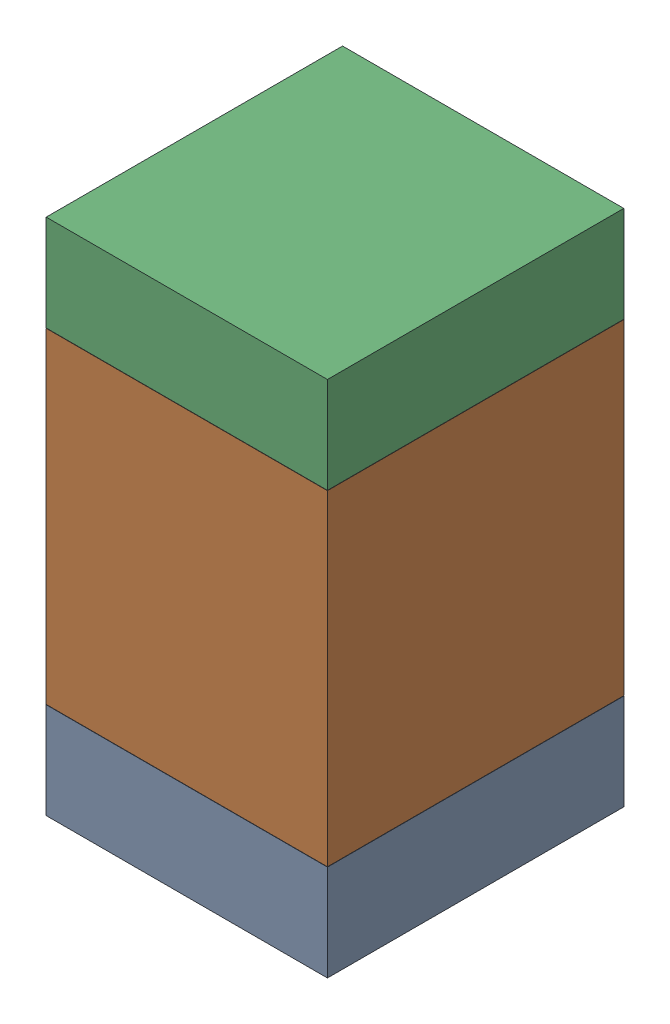
SolidWorks assembly R3, configuration Default. Lengths in mm.
Overall size (0.95 1.75 1).
6 component instances, 2 part files, 0 mates.
Components (placement in the parent):
- 6575495072-1: 6575495072 [Default] at (3.683 42.5945 0) size (0.95 0.32 1)
  - Extruded_6-1: Extruded_6 [Default] at origin size (0.95 0.32 1)
- 6575494912-1: 6575494912 [Default] at (3.683 43.307 0) size (0.95 1.1 1)
  - Extruded_7-1: Extruded_7 [Default] at origin size (0.95 1.1 1)
- 6575495072-2: 6575495072 [Default] at (3.683 44.0195 0) size (0.95 0.32 1)
  - Extruded_6-1: Extruded_6 [Default] at origin size (0.95 0.32 1)
